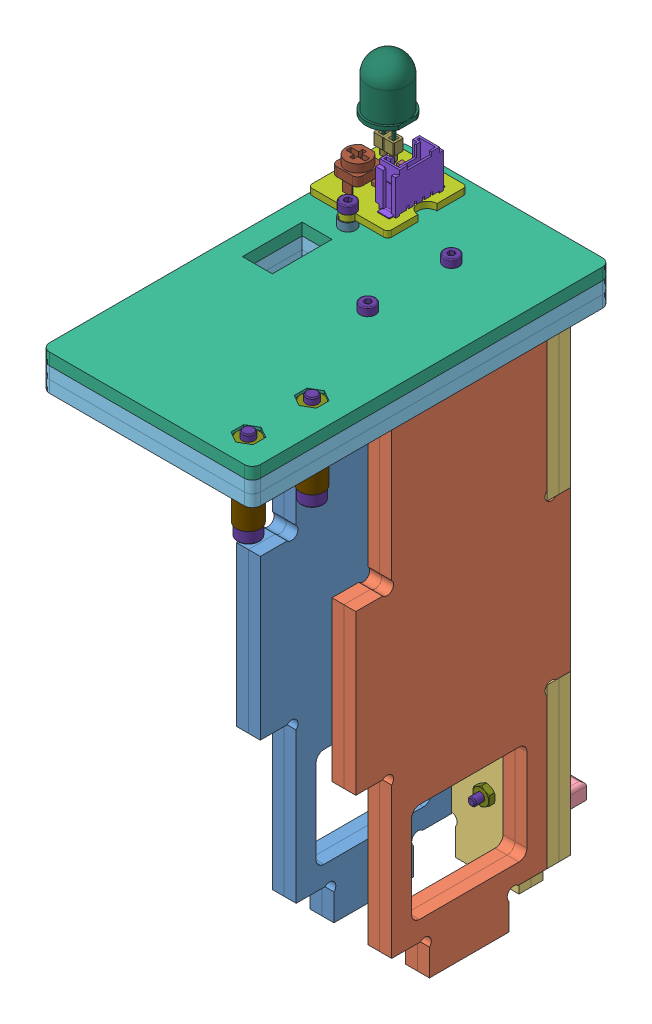
SolidWorks assembly pilier_droit, configuration Défaut. Lengths in mm.
Overall size (53 165.17 99).
42 component instances, 19 part files, 81 mates.
Components (placement in the parent):
- pilier-cote-2-1: pilier-cote-2 [Défaut] at (-45.8322 -68.3923 0) size (3 133 54)
- pilier-cote-3-2: pilier-cote-3 [Défaut] at (-18.8322 -68.3923 0) size (3 133 54)
- pilier-devant-1: pilier-devant [Défaut] at (-45.8322 -68.3923 -54) size (30 133 3)
- pilier-devant-2: pilier-devant [Défaut] at (-45.8322 -68.3923 -51) size (30 133 3)
- pilier-cote-2-3: pilier-cote-2 [Défaut] at (-42.8322 -68.3923 0) size (3 133 54)
- pilier-cote-3-4: pilier-cote-3 [Défaut] at (-21.8322 -68.3923 0) size (3 133 54)
- equerre-1: equerre [Défaut] at (-30.8322 -59.3923 -54) x (-1 0 0) z (0 0 -1) size (10 14 14)
- pilier_droit-chapeau-1-1: pilier_droit-chapeau-1 [Défaut] at (-63.8322 60.6077 31) size (53 3 90)
- pilier_droit-chapeau-1-2: pilier_droit-chapeau-1 [Défaut] at (-63.8322 63.6077 31) size (53 3 90)
- pilier_droit-chapeau-2-1: pilier_droit-chapeau-2 [Défaut] at (-63.8322 66.6077 31) size (53 3 90)
- Grove support LED-1: Grove support LED [Défaut] at (-59.2877 75.7919 -44) size (20 13.2 23.6)
  - PCB grove 20x20-1: PCB grove 20x20 [Défaut] at (7.4555 -4.1841 0) size (20 1.6 23.6)
  - Connecteur Grove (droit CMS)-1: Connecteur Grove (droit CMS) [Défaut] at (10.4555 -2.5841 0) x (-1 0 0) z (0 1 0) size (6.5 14 10)
  - 603 resistor 102-2: 603 resistor 102 [Default] at (3.6365 -2.5841 -1.49) size (2.36 0.62 1.03)
  - 603 cap on pad-1: 603 cap on pad [Défaut] at (8.4655 -2.5841 -6.62) x (0 0 1) z (-1 0 0) size (2.76 0.91 1.12)
  - 603 resistor 102-3: 603 resistor 102 [Default] at (6.6365 -2.5841 -1.49) size (2.36 0.62 1.03)
  - 603 resistor 102-4: 603 resistor 102 [Default] at (6.6365 -2.5841 -2.99) size (2.36 0.62 1.03)
  - Pot - RES_VAR1-1: Pot - RES_VAR1 [Défaut] at (4.0824 2.7159 4.0972) size (6.5 10.5 7.06)
  - Contact F-1: Contact F [Défaut] at (0.621 0.0871 -5.7728) size (2.54 7.5 2.54)
  - ssot3-1: ssot3 [Default] at (6.0932 -2.5841 -5.7439) size (3 1.13 3.09)
  - Contact F-2: Contact F [Défaut] at (3.161 0.0871 -5.7728) size (2.54 7.5 2.54)
- entretoise-grove-1: entretoise-grove [Défaut] at (-51.8322 71.6077 -34) x (1 0 0) z (0 -1 0) size (4 4 2)
- chapeau_pilier_droit-led_jaune-10-1: chapeau_pilier_droit-led_jaune-10 [Default] at (-57.5966 83.2789 -49.8228) x (1 0 0) z (0 1 0) size (10.5 11 23.5)
- entretoise-grove-2: entretoise-grove [Défaut] at (-51.8322 71.6077 -54) x (1 0 0) z (0 -1 0) size (4 4 2)
- ecrou-h-1: ecrou-h [6007 HU M2] at (-51.8322 60.6077 -54) x (0.5 0 0.866025) z (-0.866025 0 0.5) size (4 1.6 4.62)
- vis-chc-1: vis-chc [Vis CHC M2x16] at (-51.8322 73.2077 -54) x (0.657231 0 0.753689) z (-0.753689 0 0.657231) size (3.8 18 3.8)
- vis-chc-2: vis-chc [Vis CHC M2x16] at (-51.8322 73.2077 -34) x (0.657231 0 0.753689) z (-0.753689 0 0.657231) size (3.8 18 3.8)
- ecrou-h-2: ecrou-h [6007 HU M2] at (-51.8322 60.6077 -34) x (-0.866025 0 0.5) z (-0.5 0 -0.866025) size (4 1.6 4.62)
- vis-chc-3: vis-chc [Vis CHC M3x20] at (-18.8322 50.6077 24) x (-0.990761 0 0.135623) z (0.135623 0 0.990761) size (5.5 23 5.5)
- vis-chc-4: vis-chc [Vis CHC M3x20] at (-18.8322 50.6077 8) x (-0.990761 0 0.135623) z (0.135623 0 0.990761) size (5.5 23 5.5)
- ecrou-h-4: ecrou-h [6012 HU M3] at (-18.8322 69.0077 8) x (0.5 0 0.866025) z (-0.866025 0 0.5) size (5.5 2.4 6.35)
- ecrou-h-5: ecrou-h [6012 HU M3] at (-18.8322 69.0077 24) x (-0.5 0 0.866025) z (-0.866025 0 -0.5) size (5.5 2.4 6.35)
- ecrou-h-6: ecrou-h [6007 HU M2] at (-30.8322 51.6077 -46) x (-0.866025 0.5 0) z (-0.5 -0.866025 0) size (4 1.6 4.62)
- ecrou-h-7: ecrou-h [6007 HU M2] at (-30.8322 58.6077 -39) x (0 0 -1) z (1 0 0) size (4 1.6 4.62)
- vis-chc-5: vis-chc [Vis CHC M2x12] at (-30.8322 51.6077 -54) x (0.657231 0.753689 0) z (-0.753689 0.657231 0) size (3.8 14 3.8)
- vis-chc-6: vis-chc [Vis CHC M2x16] at (-30.8322 69.6077 -39) x (-0.137988 0 -0.990434) z (0.990434 0 -0.137988) size (3.8 18 3.8)
- vis-chc-7: vis-chc [Vis CHC M2x16] at (-30.8322 69.6077 -18) x (-0.137988 0 -0.990434) z (0.990434 0 -0.137988) size (3.8 18 3.8)
- grille-patin-1: grille-patin [Défaut] at (-18.8322 60.6077 8) x (0.804119 0 0.594469) z (0 -1 0) size (6 6 10)
- grille-patin-2: grille-patin [Défaut] at (-18.8322 60.6077 24) x (-0.010244 0 0.999948) z (0 -1 0) size (6 6 10)
- equerre-double_ecrou-2: equerre-double_ecrou [Défaut] at (-30.8322 60.6077 -48) x (-1 0 0) z (0 0 1) size (10 14 14)
- vis-chc-8: vis-chc [Vis CHC M2x12] at (-30.8322 -50.3923 -56) x (0.657231 0.753689 0) z (-0.753689 0.657231 0) size (3.8 14 3.8)
- ecrou-h-8: ecrou-h [6007 HU M2] at (-30.8322 -50.3923 -46.4) x (0.5 -0.866025 0) z (-0.866025 -0.5 0) size (4 1.6 4.62)
Mates (geometry in assembly coordinates):
- Coïncidente1: coincident aligned: plane of pilier-cote-2-1 through (-42.8322 60.6077 -40.7627) normal (0 1 0); plane of pilier-devant-1 through (-41.0949 60.6077 -51) normal (0 1 0)
- Coïncidente2: coincident aligned: plane of pilier-cote-2 through (-15.8322 60.6077 -40.7627) normal (0 1 0); plane of pilier-devant-1 through (-20.5694 60.6077 -51) normal (0 1 0)
- Coïncidente3: coincident aligned: plane of pilier-cote-2-1 through (-45.8322 -20.5236 -49.1314) normal (-1 0 0); plane of pilier-devant-1 through (-45.8322 20.6077 -51) normal (-1 0 0)
- Coïncidente4: coincident aligned: plane of pilier-cote-2-1 through (-42.8322 20.6077 -54) normal (0 0 -1); plane of pilier-devant-1 through (-21.7008 -60.5236 -54) normal (0 0 -1)
- Coïncidente5: coincident aligned: plane of pilier-cote-2 through (-15.8322 20.6077 -54) normal (0 0 -1); plane of pilier-devant-1 through (-21.7008 -60.5236 -54) normal (0 0 -1)
- Coïncidente6: coincident aligned: plane of pilier-cote-2 through (-15.8322 -20.5236 -49.1314) normal (1 0 0); plane of pilier-devant-1 through (-15.8322 20.6077 -51) normal (1 0 0)
- Coïncidente7: coincident anti-aligned: plane of pilier-devant-1 through (-21.7008 -60.5236 -51) normal (0 0 1); plane of pilier-devant-2 through (-21.7008 -60.5236 -51) normal (0 0 -1)
- Coïncidente8: coincident aligned: plane of pilier-devant-1 through (-38.8322 64.6077 -51) normal (0 1 0); plane of pilier-devant-2 through (-38.8322 64.6077 -48) normal (0 1 0)
- Coïncidente9: coincident aligned: plane of pilier-devant-1 through (-15.8322 20.6077 -51) normal (1 0 0); plane of pilier-devant-2 through (-15.8322 20.6077 -48) normal (1 0 0)
- Coïncidente11: coincident anti-aligned: plane of pilier-cote-2-1 through (-42.8322 -20.5236 -49.1314) normal (1 0 0); plane of pilier-cote-2-3 through (-42.8322 -20.5236 -49.1314) normal (-1 0 0)
- Coïncidente12: coincident aligned: plane of pilier-cote-2-1 through (-42.8322 64.6077 -18.5) normal (0 1 0); plane of pilier-cote-2-3 through (-39.8322 64.6077 -18.5) normal (0 1 0)
- Coïncidente13: coincident aligned: plane of pilier-cote-2-1 through (-42.8322 20.6077 -54) normal (0 0 -1); plane of pilier-cote-2-3 through (-39.8322 20.6077 -54) normal (0 0 -1)
- Coïncidente14: coincident anti-aligned: plane of pilier-cote-2 through (-18.8322 -20.5236 -49.1314) normal (-1 0 0); plane of pilier-cote-4 through (-18.8322 -20.5236 -49.1314) normal (1 0 0)
- Coïncidente15: coincident aligned: plane of pilier-cote-2 through (-15.8322 64.6077 -18.5) normal (0 1 0); plane of pilier-cote-4 through (-18.8322 64.6077 -18.5) normal (0 1 0)
- Coïncidente16: coincident: line of pilier-cote-2 through (-18.8322 22.8705 -48) axis (0 1 0); plane of pilier-cote-4 through (-18.8322 60.6077 -48) normal (0 0 -1)
- Coïncidente17: coincident anti-aligned: plane of pilier-devant-1 through (-21.7008 -60.5236 -54) normal (0 0 -1); plane of equerre-1 through (-30.8322 -59.3923 -54) normal (0 0 1)
- Coïncidente18: coincident aligned: plane of pilier-devant-1 through (-20.5694 -59.3923 -51) normal (0 -1 0); plane of equerre-1 through (-25.8322 -59.3923 -58) normal (0 -1 0)
- Coaxiale1: concentric anti-aligned: cylinder of pilier-devant-1 through (-30.8322 -50.3923 -54) axis (0 0 1) radius 1.1; cylinder of equerre-1 through (-30.8322 -50.3923 -54) axis (0 0 -1) radius 1.1
- Coïncidente19: coincident anti-aligned: plane of pilier-devant-2 through (-21.7008 -60.5236 -48) normal (0 0 1); plane of chapeau_pilier_droit-1 through (-25.0949 63.6077 -48) normal (0 0 -1)
- Coïncidente20: coincident anti-aligned: plane of pilier-devant-1 through (-38.8322 62.8705 -51) normal (-1 0 0); plane of chapeau_pilier_droit-1 through (-38.8322 63.6077 -51.7373) normal (1 0 0)
- Coïncidente21: coincident anti-aligned: plane of pilier-devant-1 through (-41.0949 60.6077 -51) normal (0 1 0); plane of chapeau_pilier_droit-1 through (-12.8322 60.6077 -57) normal (0 -1 0)
- Coïncidente22: coincident anti-aligned: plane of chapeau_pilier_droit-1 through (-12.8322 63.6077 -57) normal (0 1 0); plane of chapeau_pilier_droit-2 through (-12.8322 63.6077 -57) normal (0 -1 0)
- Coïncidente23: coincident aligned: plane of chapeau_pilier_droit-1 through (-63.8322 63.6077 -57) normal (-1 0 0); plane of chapeau_pilier_droit-2 through (-63.8322 66.6077 -57) normal (-1 0 0)
- Coïncidente24: coincident aligned: plane of chapeau_pilier_droit-1 through (-61.8322 63.6077 -59) normal (0 0 -1); plane of chapeau_pilier_droit-2 through (-61.8322 66.6077 -59) normal (0 0 -1)
- Coïncidente25: coincident anti-aligned: plane of chapeau_pilier_droit-2 through (-12.8322 66.6077 -57) normal (0 1 0); plane of pilier_droit-chapeau-2-1 through (-12.8322 66.6077 -57) normal (0 -1 0)
- Coïncidente26: coincident aligned: plane of chapeau_pilier_droit-2 through (-63.8322 66.6077 -57) normal (-1 0 0); plane of pilier_droit-chapeau-2-1 through (-63.8322 69.6077 -57) normal (-1 0 0)
- Coïncidente27: coincident aligned: plane of chapeau_pilier_droit-2 through (-61.8322 66.6077 -59) normal (0 0 -1); plane of pilier_droit-chapeau-2-1 through (-61.8322 69.6077 -59) normal (0 0 -1)
- Coaxiale2: concentric anti-aligned: cylinder of Grove support LED-1/PCB grove 20x20-1 through (-51.8322 73.2077 -34) axis (0 -1 0) radius 1.1; cylinder of entretoise-grove-1 through (-51.8322 69.6077 -34) axis (0 1 0) radius 1.1
- Distance1: distance = 5 mm: line of Grove support LED-1/Contact F-2 through (-55.8266 78.2789 -50.0728) axis (-1 0 0); line of chapeau_pilier_droit-led_jaune-10-1 through (-56.3266 73.2789 -50.0728) axis (1 0 0)
- Coaxiale3: concentric anti-aligned: cylinder of Grove support LED-1/PCB grove 20x20-1 through (-51.8322 73.2077 -54) axis (0 -1 0) radius 1.1; cylinder of entretoise-grove-2 through (-51.8322 69.6077 -54) axis (0 1 0) radius 1.1
- Coïncidente28: coincident anti-aligned: plane of Grove support LED-1/PCB grove 20x20-1 through (-51.8322 71.6077 -44) normal (0 -1 0); plane of entretoise-grove-1 through (-51.8322 71.6077 -34) normal (0 1 0)
- Coïncidente29: coincident anti-aligned: plane of Grove support LED-1/Contact F-2 through (-55.8266 78.6789 -49.4728) normal (-1 0 0); plane of chapeau_pilier_droit-led_jaune-10-1 through (-55.8266 83.2789 -50.0728) normal (1 0 0)
- Coïncidente30: coincident anti-aligned: plane of Grove support LED-1/Contact F-2 through (-56.4266 78.6789 -50.0728) normal (0 0 1); plane of chapeau_pilier_droit-led_jaune-10-1 through (-57.5966 83.2789 -50.0728) normal (0 0 -1)
- Coïncidente31: coincident anti-aligned: plane of Grove support LED-1/PCB grove 20x20-1 through (-51.8322 71.6077 -44) normal (0 -1 0); plane of entretoise-grove-2 through (-51.8322 71.6077 -54) normal (0 1 0)
- Coïncidente32: coincident anti-aligned: plane of pilier_droit-chapeau-2-1 through (-12.8322 69.6077 -57) normal (0 1 0); plane of entretoise-grove-2 through (-51.8322 69.6077 -54) normal (0 -1 0)
- Coaxiale4: concentric aligned: cylinder of pilier_droit-chapeau-2-1 through (-51.8322 66.6077 -54) axis (0 1 0) radius 1.1; cylinder of entretoise-grove-2 through (-51.8322 69.6077 -54) axis (0 1 0) radius 1.1
- Coaxiale5: concentric anti-aligned: cylinder of pilier_droit-chapeau-2-1 through (-51.8322 66.6077 -34) axis (0 1 0) radius 1.1; cylinder of Grove support LED-1/PCB grove 20x20-1 through (-51.8322 73.2077 -34) axis (0 -1 0) radius 1.1
- Coaxiale6: concentric anti-aligned: cylinder of Grove support LED-1/PCB grove 20x20-1 through (-51.8322 73.2077 -34) axis (0 -1 0) radius 1.1; cylinder of vis-chc-2 through (-51.8322 57.2077 -34) axis (0 1 0) radius 1
- Coaxiale7: concentric anti-aligned: cylinder of Grove support LED-1/PCB grove 20x20-1 through (-51.8322 73.2077 -54) axis (0 -1 0) radius 1.1; cylinder of vis-chc-1 through (-51.8322 57.2077 -54) axis (0 1 0) radius 1
- Coïncidente33: coincident anti-aligned: plane of Grove support LED-1/PCB grove 20x20-1 through (-51.8322 73.2077 -44) normal (0 1 0); plane of vis-chc-2 through (-51.8322 73.2077 -34) normal (0 -1 0)
- Coïncidente34: coincident anti-aligned: plane of Grove support LED-1/PCB grove 20x20-1 through (-51.8322 73.2077 -44) normal (0 1 0); plane of vis-chc-1 through (-51.8322 73.2077 -54) normal (0 -1 0)
- Coïncidente35: coincident anti-aligned: plane of chapeau_pilier_droit-1 through (-12.8322 60.6077 -57) normal (0 -1 0); plane of ecrou-h-1 through (-49.8322 60.6077 -52.8453) normal (0 1 0)
- Coaxiale8: concentric aligned: cylinder of ecrou-h-1 through (-51.8322 59.0077 -54) axis (0 1 0) radius 0.7835; cylinder of vis-chc-1 through (-51.8322 57.2077 -54) axis (0 1 0) radius 1
- Parallèle1: parallel aligned: plane of chapeau_pilier_droit-1 through (-63.8322 63.6077 -57) normal (-1 0 0); plane of ecrou-h-1 through (-53.8322 59.0077 -55.1547) normal (-1 0 0)
- Coïncidente37: coincident anti-aligned: plane of chapeau_pilier_droit-1 through (-12.8322 60.6077 -57) normal (0 -1 0); plane of ecrou-h-2 through (-52.9869 60.6077 -32) normal (0 1 0)
- Coaxiale9: concentric aligned: cylinder of vis-chc-2 through (-51.8322 57.2077 -34) axis (0 1 0) radius 1; cylinder of ecrou-h-2 through (-51.8322 59.0077 -34) axis (0 1 0) radius 0.7835
- Parallèle2: parallel aligned: plane of chapeau_pilier_droit-1 through (-61.8322 63.6077 -59) normal (0 0 -1); plane of ecrou-h-2 through (-50.6775 59.0077 -36) normal (0 0 -1)
- Coaxiale10: concentric anti-aligned: cylinder of chapeau_pilier_droit-1 through (-18.8322 63.6077 24) axis (0 -1 0) radius 1.6; cylinder of entretoise-6x10-2 through (-18.8322 50.6077 24) axis (0 1 0) radius 2
- Coaxiale11: concentric anti-aligned: cylinder of chapeau_pilier_droit-1 through (-18.8322 63.6077 8) axis (0 -1 0) radius 1.6; cylinder of entretoise-6x10-1 through (-18.8322 50.6077 8) axis (0 1 0) radius 2
- Coïncidente39: coincident anti-aligned: plane of chapeau_pilier_droit-1 through (-12.8322 60.6077 -57) normal (0 -1 0); plane of entretoise-6x10-2 through (-18.8322 60.6077 24) normal (0 1 0)
- Coïncidente40: coincident anti-aligned: plane of chapeau_pilier_droit-1 through (-12.8322 60.6077 -57) normal (0 -1 0); plane of entretoise-6x10-1 through (-18.8322 60.6077 8) normal (0 1 0)
- Coaxiale12: concentric anti-aligned: cylinder of entretoise-6x10-2 through (-18.8322 50.6077 24) axis (0 1 0) radius 2; cylinder of vis-chc-3 through (-18.8322 70.6077 24) axis (0 -1 0) radius 1.5
- Coïncidente41: coincident anti-aligned: plane of entretoise-6x10-2 through (-18.8322 50.6077 24) normal (0 -1 0); plane of vis-chc-3 through (-18.8322 50.6077 24) normal (0 1 0)
- Coaxiale13: concentric anti-aligned: cylinder of entretoise-6x10-1 through (-18.8322 50.6077 8) axis (0 1 0) radius 2; cylinder of vis-chc-4 through (-18.8322 70.6077 8) axis (0 -1 0) radius 1.5
- Coïncidente42: coincident anti-aligned: plane of entretoise-6x10-1 through (-18.8322 50.6077 8) normal (0 -1 0); plane of vis-chc-4 through (-18.8322 50.6077 8) normal (0 1 0)
- Coaxiale14: concentric anti-aligned: cylinder of vis-chc-4 through (-18.8322 70.6077 8) axis (0 -1 0) radius 1.5; cylinder of ecrou-h-4 through (-18.8322 66.6077 8) axis (0 1 0) radius 1.2295
- Parallèle3: parallel anti-aligned: plane of pilier_droit-chapeau-2-1 through (-21.8633 66.6077 6.3471) normal (1 0 0); plane of ecrou-h-4 through (-21.5822 66.6077 6.4123) normal (-1 0 0)
- Coaxiale15: concentric anti-aligned: cylinder of vis-chc-3 through (-18.8322 70.6077 24) axis (0 -1 0) radius 1.5; cylinder of ecrou-h-5 through (-18.8322 66.6077 24) axis (0 1 0) radius 1.2295
- Parallèle4: parallel anti-aligned: plane of pilier_droit-chapeau-2-1 through (-21.8633 66.6077 22.25) normal (1 0 0); plane of ecrou-h-5 through (-21.5822 66.6077 22.4123) normal (-1 0 0)
- Coïncidente45: coincident anti-aligned: plane of chapeau_pilier_droit-2 through (-12.8322 66.6077 -57) normal (0 1 0); plane of ecrou-h-5 through (-18.8322 66.6077 27.1754) normal (0 -1 0)
- Coïncidente46: coincident anti-aligned: plane of chapeau_pilier_droit-2 through (-12.8322 66.6077 -57) normal (0 1 0); plane of ecrou-h-4 through (-16.0822 66.6077 9.5877) normal (0 -1 0)
- Coaxiale16: concentric aligned: cylinder of pilier-devant-2 through (-30.8322 51.6077 -51) axis (0 0 1) radius 1.1; cylinder of equerre-double_ecrou-2 through (-30.8322 51.6077 -48) axis (0 0 1) radius 1.1
- Coïncidente47: coincident anti-aligned: plane of pilier-devant-2 through (-21.7008 -60.5236 -48) normal (0 0 1); plane of equerre-double_ecrou-2 through (-30.8322 60.6077 -48) normal (0 0 -1)
- Coïncidente48: coincident anti-aligned: plane of chapeau_pilier_droit-1 through (-12.8322 60.6077 -57) normal (0 -1 0); plane of equerre-double_ecrou-2 through (-25.8322 60.6077 -44) normal (0 1 0)
- Coaxiale17: concentric anti-aligned: cylinder of equerre-double_ecrou-2 through (-30.8322 51.6077 -48) axis (0 0 1) radius 1.1; cylinder of ecrou-h-6 through (-30.8322 51.6077 -44.4) axis (0 0 -1) radius 0.7835
- Parallèle5: parallel anti-aligned: plane of equerre-double_ecrou-2 through (-29.5822 49.4427 -46) normal (-0.866025 0.5 0); plane of ecrou-h-6 through (-28.5228 51.6077 -44.4) normal (0.866025 -0.5 0)
- Coïncidente51: coincident anti-aligned: plane of equerre-double_ecrou-2 through (-30.8322 60.6077 -46) normal (0 0 1); plane of ecrou-h-6 through (-31.9869 53.6077 -46) normal (0 0 -1)
- Coaxiale18: concentric anti-aligned: cylinder of equerre-double_ecrou-2 through (-30.8322 60.6077 -39) axis (0 -1 0) radius 1.1; cylinder of ecrou-h-7 through (-30.8322 57.0077 -39) axis (0 1 0) radius 0.7835
- Parallèle6: parallel anti-aligned: plane of equerre-double_ecrou-2 through (-32.0822 58.6077 -41.1651) normal (0 0 1); plane of ecrou-h-7 through (-29.6775 57.0077 -41) normal (0 0 -1)
- Coïncidente53: coincident anti-aligned: plane of equerre-double_ecrou-2 through (-30.8322 58.6077 -48) normal (0 -1 0); plane of ecrou-h-7 through (-31.9869 58.6077 -41) normal (0 1 0)
- Coaxiale19: concentric anti-aligned: cylinder of pilier-devant-1 through (-30.8322 51.6077 -54) axis (0 0 1) radius 1.1; cylinder of vis-chc-5 through (-30.8322 51.6077 -42) axis (0 0 -1) radius 1
- Coïncidente54: coincident anti-aligned: plane of pilier-devant-1 through (-21.7008 -60.5236 -54) normal (0 0 -1); plane of vis-chc-5 through (-30.8322 51.6077 -54) normal (0 0 1)
- Coaxiale20: concentric aligned: cylinder of pilier_droit-chapeau-2-1 through (-30.8322 66.6077 -39) axis (0 1 0) radius 1.1; cylinder of vis-chc-6 through (-30.8322 53.6077 -39) axis (0 1 0) radius 1
- Coïncidente55: coincident anti-aligned: plane of pilier_droit-chapeau-2-1 through (-12.8322 69.6077 -57) normal (0 1 0); plane of vis-chc-6 through (-30.8322 69.6077 -39) normal (0 -1 0)
- Coaxiale21: concentric aligned: cylinder of pilier_droit-chapeau-2-1 through (-30.8322 66.6077 -18) axis (0 1 0) radius 1.1; cylinder of vis-chc-7 through (-30.8322 53.6077 -18) axis (0 1 0) radius 1
- Coïncidente56: coincident anti-aligned: plane of pilier_droit-chapeau-2-1 through (-12.8322 69.6077 -57) normal (0 1 0); plane of vis-chc-7 through (-30.8322 69.6077 -18) normal (0 -1 0)
- Coaxiale22: concentric aligned: cylinder of equerre-1 through (-30.8322 -50.3923 -54) axis (0 0 -1) radius 1.1; cylinder of vis-chc-8 through (-30.8322 -50.3923 -44) axis (0 0 -1) radius 1
- Coïncidente57: coincident anti-aligned: plane of equerre-1 through (-30.8322 -50.3923 -56) normal (0 0 -1); plane of vis-chc-8 through (-30.8322 -50.3923 -56) normal (0 0 1)
- Coaxiale23: concentric anti-aligned: cylinder of vis-chc-8 through (-30.8322 -50.3923 -44) axis (0 0 -1) radius 1; cylinder of ecrou-h-8 through (-30.8322 -50.3923 -48) axis (0 0 1) radius 0.7835
- Coïncidente58: coincident anti-aligned: plane of pilier-devant-2 through (-21.7008 -60.5236 -48) normal (0 0 1); plane of ecrou-h-8 through (-28.8322 -51.547 -48) normal (0 0 -1)
- Parallèle7: parallel aligned: plane of pilier-devant-2 through (-45.8322 -19.3923 -48) normal (-1 0 0); plane of ecrou-h-8 through (-32.8322 -49.2375 -48) normal (-1 0 0)
